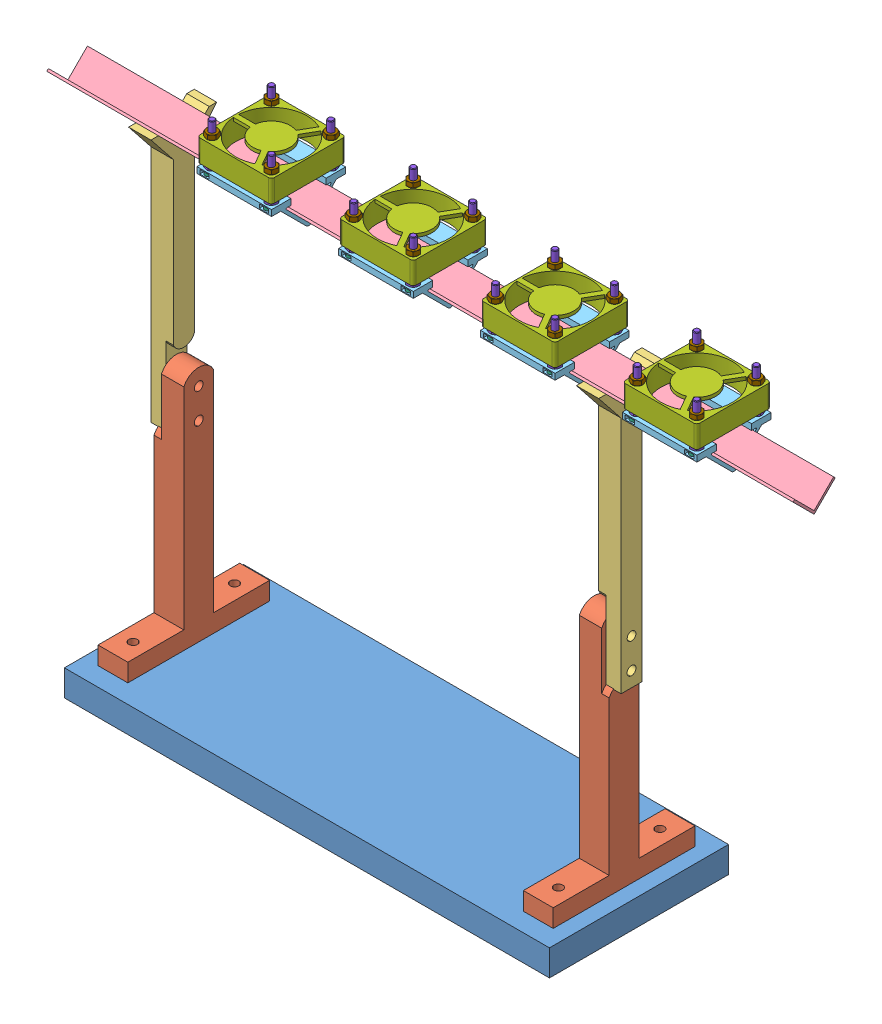
SolidWorks assembly Cooling Assembly V3, configuration Default. Lengths in mm.
Overall size (500 559.79 513.16).
66 component instances, 9 part files, 11 mates.
Components (placement in the parent):
- MDF-Board_Small-1: MDF-Board_Small [Default] at (111.619 187.1312 255.4177) size (325 17.5 120)
- Y-Bracket_Frame-1: Y-Bracket_Frame [Default] at (-20.881 485.8786 255.4177) x (0 0 1) z (-1 0 0) size (95 159.42 20)
- AlExtrusion_Y-Mount-1: AlExtrusion_Y-Mount [Default] at (-45.881 485.8786 255.4177) x (0 0 -1) z (1 0 0) size (44 178.83 15)
- 20x20x1.5mm_Al-extrusion-1: 20x20x1.5mm_Al-extrusion [Half 0.5m] at (-108.5491 484.8786 255.4177) x (0 0.707107 0.707107) z (-1 0 0) size (543.47 182.25 500)
- AlExtrusion_Y-Mount-2: AlExtrusion_Y-Mount [Default] at (269.119 485.8786 255.4177) x (0 0 1) z (-1 0 0) size (44 178.83 15)
- Y-Bracket_Frame-3: Y-Bracket_Frame [Default] at (244.119 485.8786 255.4177) x (0 0 -1) z (1 0 0) size (95 159.42 20)
- MagneticFanMountAssy-1: MagneticFanMountAssy [Default] at (-15.8272 470.5462 277.8238) x (0 -0.707107 -0.707107) z (1 0 0) size (64.28 63.52 58.35)
  - FanBracket-V2^Cooling Assembly V3-1: FanBracket-V2^Cooling Assembly V3 [Default] at (8.1232 26.9781 67.9327) size (37.91 37.91 50)
  - Circular_Magnet-2: Circular_Magnet [Default] at (27.0405 70.0117 84.7101) x (0.707107 0.707107 0) z (0 0 1) size (5 2.5 5)
  - Circular_Magnet-3: Circular_Magnet [Default] at (-37.471 5.5001 41.0053) x (-0.707107 -0.707107 0) z (0 0 -1) size (5 2.5 5)
  - Circular_Magnet-4: Circular_Magnet [Default] at (27.0405 70.0117 44.8601) x (0.707107 0.707107 0) z (0 0 1) size (5 2.5 5)
  - Circular_Magnet-5: Circular_Magnet [Default] at (-37.471 5.5001 1.1553) x (-0.707107 -0.707107 0) z (0 0 -1) size (5 2.5 5)
  - Axial-fan-1: Axial-fan [Default] at (-9.4225 41.9632 43.0577) x (0.707107 0.707107 0) z (0 0 1) size (74.93 14.9 57.96)
  - hexagon head bolt (grades a and b)_as-1: hexagon head bolt (grades a and b)_as [AS 1110.1 - M4 x 25-N] at (-21.5317 25.8942 62.9827) x (-0.707107 0.707107 0) z (0.484701 0.484701 0.7281) size (27.8 8.08 7)
  - hexagon nut style 1 (grades a and b) as-2: hexagon nut style 1 (grades a and b) as [AS 1112.1 S1 - M4-W-N] at (-36.3103 40.6727 62.9827) x (0.5 0.5 0.707107) z (-0.707107 0.707107 0) size (7 8.08 3.2)
  - hexagon head bolt (grades a and b)_as-2: hexagon head bolt (grades a and b)_as [AS 1110.1 - M4 x 25-N] at (6.6465 54.0724 62.9827) x (-0.707107 0.707107 0) z (0.484701 0.484701 -0.7281) size (27.8 8.08 7)
  - hexagon nut style 1 (grades a and b) as-3: hexagon nut style 1 (grades a and b) as [AS 1112.1 S1 - M4-W-N] at (-8.1321 68.8509 62.9827) x (0.5 0.5 -0.707107) z (-0.707107 0.707107 0) size (7 8.08 3.2)
  - hexagon head bolt (grades a and b)_as-3: hexagon head bolt (grades a and b)_as [AS 1110.1 - M4 x 25-N] at (6.6465 54.0724 23.1327) x (-0.707107 0.707107 0) z (-0.484701 -0.484701 -0.7281) size (27.8 8.08 7)
  - hexagon nut style 1 (grades a and b) as-4: hexagon nut style 1 (grades a and b) as [AS 1112.1 S1 - M4-W-N] at (-8.1321 68.8509 23.1327) x (-0.5 -0.5 -0.707107) z (-0.707107 0.707107 0) size (7 8.08 3.2)
  - hexagon head bolt (grades a and b)_as-4: hexagon head bolt (grades a and b)_as [AS 1110.1 - M4 x 25-N] at (-21.5317 25.8942 23.1327) x (-0.707107 0.707107 0) z (-0.484701 -0.484701 0.7281) size (27.8 8.08 7)
  - hexagon nut style 1 (grades a and b) as-5: hexagon nut style 1 (grades a and b) as [AS 1112.1 S1 - M4-W-N] at (-36.3103 40.6727 23.1327) x (-0.5 -0.5 0.707107) z (-0.707107 0.707107 0) size (7 8.08 3.2)
- MagneticFanMountAssy-2: MagneticFanMountAssy [Default] at (79.1728 470.5462 277.8238) x (0 -0.707107 -0.707107) z (1 0 0) size (64.28 63.52 58.35)
  - FanBracket-V2^Cooling Assembly V3-1: FanBracket-V2^Cooling Assembly V3 [Default] at (8.1232 26.9781 67.9327) size (37.91 37.91 50)
  - Circular_Magnet-2: Circular_Magnet [Default] at (27.0405 70.0117 84.7101) x (0.707107 0.707107 0) z (0 0 1) size (5 2.5 5)
  - Circular_Magnet-3: Circular_Magnet [Default] at (-37.471 5.5001 41.0053) x (-0.707107 -0.707107 0) z (0 0 -1) size (5 2.5 5)
  - Circular_Magnet-4: Circular_Magnet [Default] at (27.0405 70.0117 44.8601) x (0.707107 0.707107 0) z (0 0 1) size (5 2.5 5)
  - Circular_Magnet-5: Circular_Magnet [Default] at (-37.471 5.5001 1.1553) x (-0.707107 -0.707107 0) z (0 0 -1) size (5 2.5 5)
  - Axial-fan-1: Axial-fan [Default] at (-9.4225 41.9632 43.0577) x (0.707107 0.707107 0) z (0 0 1) size (74.93 14.9 57.96)
  - hexagon head bolt (grades a and b)_as-1: hexagon head bolt (grades a and b)_as [AS 1110.1 - M4 x 25-N] at (-21.5317 25.8942 62.9827) x (-0.707107 0.707107 0) z (0.484701 0.484701 0.7281) size (27.8 8.08 7)
  - hexagon nut style 1 (grades a and b) as-2: hexagon nut style 1 (grades a and b) as [AS 1112.1 S1 - M4-W-N] at (-36.3103 40.6727 62.9827) x (0.5 0.5 0.707107) z (-0.707107 0.707107 0) size (7 8.08 3.2)
  - hexagon head bolt (grades a and b)_as-2: hexagon head bolt (grades a and b)_as [AS 1110.1 - M4 x 25-N] at (6.6465 54.0724 62.9827) x (-0.707107 0.707107 0) z (0.484701 0.484701 -0.7281) size (27.8 8.08 7)
  - hexagon nut style 1 (grades a and b) as-3: hexagon nut style 1 (grades a and b) as [AS 1112.1 S1 - M4-W-N] at (-8.1321 68.8509 62.9827) x (0.5 0.5 -0.707107) z (-0.707107 0.707107 0) size (7 8.08 3.2)
  - hexagon head bolt (grades a and b)_as-3: hexagon head bolt (grades a and b)_as [AS 1110.1 - M4 x 25-N] at (6.6465 54.0724 23.1327) x (-0.707107 0.707107 0) z (-0.484701 -0.484701 -0.7281) size (27.8 8.08 7)
  - hexagon nut style 1 (grades a and b) as-4: hexagon nut style 1 (grades a and b) as [AS 1112.1 S1 - M4-W-N] at (-8.1321 68.8509 23.1327) x (-0.5 -0.5 -0.707107) z (-0.707107 0.707107 0) size (7 8.08 3.2)
  - hexagon head bolt (grades a and b)_as-4: hexagon head bolt (grades a and b)_as [AS 1110.1 - M4 x 25-N] at (-21.5317 25.8942 23.1327) x (-0.707107 0.707107 0) z (-0.484701 -0.484701 0.7281) size (27.8 8.08 7)
  - hexagon nut style 1 (grades a and b) as-5: hexagon nut style 1 (grades a and b) as [AS 1112.1 S1 - M4-W-N] at (-36.3103 40.6727 23.1327) x (-0.5 -0.5 0.707107) z (-0.707107 0.707107 0) size (7 8.08 3.2)
- MagneticFanMountAssy-3: MagneticFanMountAssy [Default] at (174.1728 470.5462 277.8238) x (0 -0.707107 -0.707107) z (1 0 0) size (64.28 63.52 58.35)
  - FanBracket-V2^Cooling Assembly V3-1: FanBracket-V2^Cooling Assembly V3 [Default] at (8.1232 26.9781 67.9327) size (37.91 37.91 50)
  - Circular_Magnet-2: Circular_Magnet [Default] at (27.0405 70.0117 84.7101) x (0.707107 0.707107 0) z (0 0 1) size (5 2.5 5)
  - Circular_Magnet-3: Circular_Magnet [Default] at (-37.471 5.5001 41.0053) x (-0.707107 -0.707107 0) z (0 0 -1) size (5 2.5 5)
  - Circular_Magnet-4: Circular_Magnet [Default] at (27.0405 70.0117 44.8601) x (0.707107 0.707107 0) z (0 0 1) size (5 2.5 5)
  - Circular_Magnet-5: Circular_Magnet [Default] at (-37.471 5.5001 1.1553) x (-0.707107 -0.707107 0) z (0 0 -1) size (5 2.5 5)
  - Axial-fan-1: Axial-fan [Default] at (-9.4225 41.9632 43.0577) x (0.707107 0.707107 0) z (0 0 1) size (74.93 14.9 57.96)
  - hexagon head bolt (grades a and b)_as-1: hexagon head bolt (grades a and b)_as [AS 1110.1 - M4 x 25-N] at (-21.5317 25.8942 62.9827) x (-0.707107 0.707107 0) z (0.484701 0.484701 0.7281) size (27.8 8.08 7)
  - hexagon nut style 1 (grades a and b) as-2: hexagon nut style 1 (grades a and b) as [AS 1112.1 S1 - M4-W-N] at (-36.3103 40.6727 62.9827) x (0.5 0.5 0.707107) z (-0.707107 0.707107 0) size (7 8.08 3.2)
  - hexagon head bolt (grades a and b)_as-2: hexagon head bolt (grades a and b)_as [AS 1110.1 - M4 x 25-N] at (6.6465 54.0724 62.9827) x (-0.707107 0.707107 0) z (0.484701 0.484701 -0.7281) size (27.8 8.08 7)
  - hexagon nut style 1 (grades a and b) as-3: hexagon nut style 1 (grades a and b) as [AS 1112.1 S1 - M4-W-N] at (-8.1321 68.8509 62.9827) x (0.5 0.5 -0.707107) z (-0.707107 0.707107 0) size (7 8.08 3.2)
  - hexagon head bolt (grades a and b)_as-3: hexagon head bolt (grades a and b)_as [AS 1110.1 - M4 x 25-N] at (6.6465 54.0724 23.1327) x (-0.707107 0.707107 0) z (-0.484701 -0.484701 -0.7281) size (27.8 8.08 7)
  - hexagon nut style 1 (grades a and b) as-4: hexagon nut style 1 (grades a and b) as [AS 1112.1 S1 - M4-W-N] at (-8.1321 68.8509 23.1327) x (-0.5 -0.5 -0.707107) z (-0.707107 0.707107 0) size (7 8.08 3.2)
  - hexagon head bolt (grades a and b)_as-4: hexagon head bolt (grades a and b)_as [AS 1110.1 - M4 x 25-N] at (-21.5317 25.8942 23.1327) x (-0.707107 0.707107 0) z (-0.484701 -0.484701 0.7281) size (27.8 8.08 7)
  - hexagon nut style 1 (grades a and b) as-5: hexagon nut style 1 (grades a and b) as [AS 1112.1 S1 - M4-W-N] at (-36.3103 40.6727 23.1327) x (-0.5 -0.5 0.707107) z (-0.707107 0.707107 0) size (7 8.08 3.2)
- MagneticFanMountAssy-4: MagneticFanMountAssy [Default] at (269.1728 470.5462 277.8238) x (0 -0.707107 -0.707107) z (1 0 0) size (64.28 63.52 58.35)
  - FanBracket-V2^Cooling Assembly V3-1: FanBracket-V2^Cooling Assembly V3 [Default] at (8.1232 26.9781 67.9327) size (37.91 37.91 50)
  - Circular_Magnet-2: Circular_Magnet [Default] at (27.0405 70.0117 84.7101) x (0.707107 0.707107 0) z (0 0 1) size (5 2.5 5)
  - Circular_Magnet-3: Circular_Magnet [Default] at (-37.471 5.5001 41.0053) x (-0.707107 -0.707107 0) z (0 0 -1) size (5 2.5 5)
  - Circular_Magnet-4: Circular_Magnet [Default] at (27.0405 70.0117 44.8601) x (0.707107 0.707107 0) z (0 0 1) size (5 2.5 5)
  - Circular_Magnet-5: Circular_Magnet [Default] at (-37.471 5.5001 1.1553) x (-0.707107 -0.707107 0) z (0 0 -1) size (5 2.5 5)
  - Axial-fan-1: Axial-fan [Default] at (-9.4225 41.9632 43.0577) x (0.707107 0.707107 0) z (0 0 1) size (74.93 14.9 57.96)
  - hexagon head bolt (grades a and b)_as-1: hexagon head bolt (grades a and b)_as [AS 1110.1 - M4 x 25-N] at (-21.5317 25.8942 62.9827) x (-0.707107 0.707107 0) z (0.484701 0.484701 0.7281) size (27.8 8.08 7)
  - hexagon nut style 1 (grades a and b) as-2: hexagon nut style 1 (grades a and b) as [AS 1112.1 S1 - M4-W-N] at (-36.3103 40.6727 62.9827) x (0.5 0.5 0.707107) z (-0.707107 0.707107 0) size (7 8.08 3.2)
  - hexagon head bolt (grades a and b)_as-2: hexagon head bolt (grades a and b)_as [AS 1110.1 - M4 x 25-N] at (6.6465 54.0724 62.9827) x (-0.707107 0.707107 0) z (0.484701 0.484701 -0.7281) size (27.8 8.08 7)
  - hexagon nut style 1 (grades a and b) as-3: hexagon nut style 1 (grades a and b) as [AS 1112.1 S1 - M4-W-N] at (-8.1321 68.8509 62.9827) x (0.5 0.5 -0.707107) z (-0.707107 0.707107 0) size (7 8.08 3.2)
  - hexagon head bolt (grades a and b)_as-3: hexagon head bolt (grades a and b)_as [AS 1110.1 - M4 x 25-N] at (6.6465 54.0724 23.1327) x (-0.707107 0.707107 0) z (-0.484701 -0.484701 -0.7281) size (27.8 8.08 7)
  - hexagon nut style 1 (grades a and b) as-4: hexagon nut style 1 (grades a and b) as [AS 1112.1 S1 - M4-W-N] at (-8.1321 68.8509 23.1327) x (-0.5 -0.5 -0.707107) z (-0.707107 0.707107 0) size (7 8.08 3.2)
  - hexagon head bolt (grades a and b)_as-4: hexagon head bolt (grades a and b)_as [AS 1110.1 - M4 x 25-N] at (-21.5317 25.8942 23.1327) x (-0.707107 0.707107 0) z (-0.484701 -0.484701 0.7281) size (27.8 8.08 7)
  - hexagon nut style 1 (grades a and b) as-5: hexagon nut style 1 (grades a and b) as [AS 1112.1 S1 - M4-W-N] at (-36.3103 40.6727 23.1327) x (-0.5 -0.5 0.707107) z (-0.707107 0.707107 0) size (7 8.08 3.2)
Mates (geometry in assembly coordinates):
- Coincident1: coincident anti-aligned: plane of MDF-Board_Small-1 through (111.619 204.6312 255.4177) normal (0 1 0); plane of Y-Bracket_Frame-1 through (-40.881 204.6312 207.9177) normal (0 -1 0)
- Distance1: distance = 10 mm aligned: plane of Y-Bracket_Frame-1 through (-40.881 353.0486 255.4177) normal (-1 0 0); plane of MDF-Board_Small-1 through (-50.881 204.6312 315.4177) normal (-1 0 0)
- Coincident3: coincident: point of MDF-Board_Small-1; moEndPointRef_w of Y-Bracket_Frame-1
- Coincident4: coincident anti-aligned: plane of Y-Bracket_Frame-1 through (-35.881 353.0486 255.4177) normal (-1 0 0); plane of AlExtrusion_Y-Mount-1 through (-35.881 378.0486 255.4177) normal (1 0 0)
- Concentric1: concentric aligned: cylinder of Y-Bracket_Frame-1 through (-40.881 353.0486 255.4177) axis (1 0 0) radius 2.925; cylinder of AlExtrusion_Y-Mount-1 through (-45.881 353.0486 255.4177) axis (1 0 0) radius 2.925
- Concentric2: concentric aligned: cylinder of Y-Bracket_Frame-1 through (-40.881 333.0486 255.4177) axis (1 0 0) radius 3; cylinder of AlExtrusion_Y-Mount-1 through (-45.881 333.0486 255.4177) axis (1 0 0) radius 3
- Coincident6: coincident anti-aligned: plane of AlExtrusion_Y-Mount-1 through (-30.881 501.8786 238.4177) normal (0 0.707107 0.707107); plane of 20x20x1.5mm_Al-extrusion-1 through (391.4509 484.8786 255.4177) normal (0 -0.707107 -0.707107)
- Coincident7: coincident anti-aligned: plane of AlExtrusion_Y-Mount-1 through (-30.881 484.8786 255.4177) normal (0 0.707107 -0.707107); plane of 20x20x1.5mm_Al-extrusion-1 through (391.4509 484.8786 255.4177) normal (0 -0.707107 0.707107)
- Coincident8: coincident anti-aligned: plane of 20x20x1.5mm_Al-extrusion-1 through (391.4509 484.8786 255.4177) normal (0 -0.707107 0.707107); plane of MagneticFanMountAssy-1/FanBracket-V2^Cooling Assembly V3-1 through (2.1055 500.0814 270.6205) normal (0 0.707107 -0.707107)
- Parallel1: parallel anti-aligned: plane of 20x20x1.5mm_Al-extrusion-1 through (391.4509 484.8786 255.4177) normal (0 -0.707107 -0.707107); plane of MagneticFanMountAssy-1/FanBracket-V2^Cooling Assembly V3-1 through (2.1055 484.2751 254.8141) normal (0 0.707107 0.707107)
- Coincident10: coincident: line of 20x20x1.5mm_Al-extrusion-1 through (391.4509 500.0814 242.3362) axis (-1 0 0); plane of MagneticFanMountAssy-1/FanBracket-V2^Cooling Assembly V3-1 through (2.1055 500.0814 239.0078) normal (0 -1 0)
